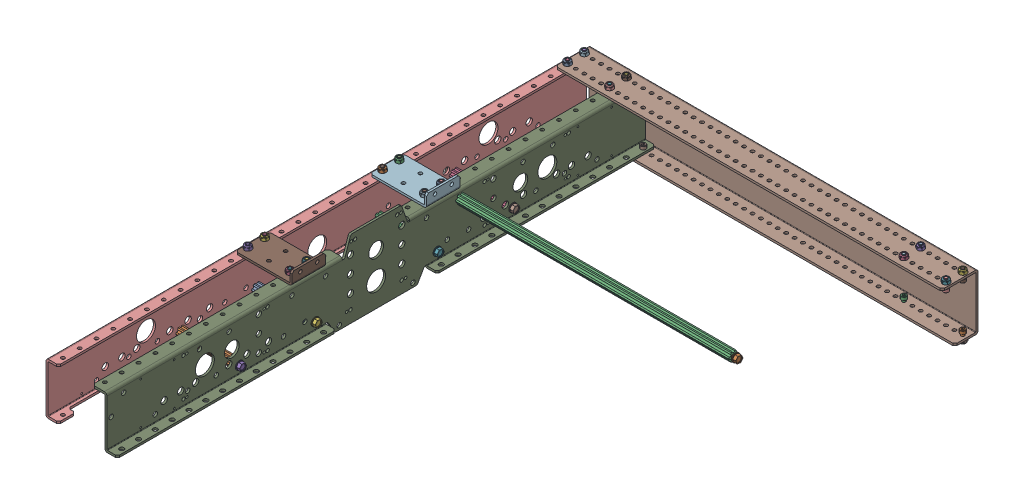
SolidWorks assembly AM14U3 Long Frame Half, configuration Default. Lengths in mm.
Overall size (596.14 116.33 816.74).
60 component instances, 9 part files, 0 mates.
Components (placement in the parent):
- Churro 3375-1: Churro 3375 [Default] at (-501.65 -66.929 448.437) x (0 0 1) z (-1 0 0) size (14.66 12.7 85.73)
- Churro 3375-2: Churro 3375 [Default] at (-501.65 -66.929 562.737) x (0 0 1) z (-1 0 0) size (14.66 12.7 85.73)
- Churro 3375-3: Churro 3375 [Default] at (-501.65 -66.929 264.287) x (0 0 1) z (-1 0 0) size (14.66 12.7 85.73)
- Churro 3375-4: Churro 3375 [Default] at (-501.65 -66.929 149.987) x (0 0 1) z (-1 0 0) size (14.66 12.7 85.73)
- FHTS 0.25-20-0.75_FHTS 0.25-20-G-0.75-C-1: FHTS 0.25-20-0.75_FHTS 0.25-20-G-0.75-C [Default] at (-498.475 -66.929 562.737) x (-1 0 0) z (0 0.924225 0.381849) size (24.64 12.19 12.19)
- FHTS 0.25-20-0.75_FHTS 0.25-20-G-0.75-C-2: FHTS 0.25-20-0.75_FHTS 0.25-20-G-0.75-C [Default] at (-498.475 -66.929 448.437) x (-1 0 0) z (0 0.924225 0.381849) size (24.64 12.19 12.19)
- FHTS 0.25-20-0.75_FHTS 0.25-20-G-0.75-C-3: FHTS 0.25-20-0.75_FHTS 0.25-20-G-0.75-C [Default] at (-498.475 -66.929 264.287) x (-1 0 0) z (0 0.924225 0.381849) size (24.64 12.19 12.19)
- FHTS 0.25-20-0.75_FHTS 0.25-20-G-0.75-C-4: FHTS 0.25-20-0.75_FHTS 0.25-20-G-0.75-C [Default] at (-498.475 -66.929 149.987) x (-1 0 0) z (0 0.924225 0.381849) size (24.64 12.19 12.19)
- FHTS 0.25-20-0.75_FHTS 0.25-20-G-0.75-C-5: FHTS 0.25-20-0.75_FHTS 0.25-20-G-0.75-C [Default] at (-590.55 -66.929 562.737) size (24.64 12.19 12.19)
- FHTS 0.25-20-0.75_FHTS 0.25-20-G-0.75-C-6: FHTS 0.25-20-0.75_FHTS 0.25-20-G-0.75-C [Default] at (-590.55 -66.929 448.437) size (24.64 12.19 12.19)
- FHTS 0.25-20-0.75_FHTS 0.25-20-G-0.75-C-7: FHTS 0.25-20-0.75_FHTS 0.25-20-G-0.75-C [Default] at (-590.55 -66.929 149.987) size (24.64 12.19 12.19)
- FHTS 0.25-20-0.75_FHTS 0.25-20-G-0.75-C-8: FHTS 0.25-20-0.75_FHTS 0.25-20-G-0.75-C [Default] at (-590.55 -66.929 264.287) size (24.64 12.19 12.19)
- FHTS 0.25-20-0.75_FHTS 0.25-20-G-0.75-C-9: FHTS 0.25-20-0.75_FHTS 0.25-20-G-0.75-C [Default] at (-501.65 -15.494 229.362) size (24.64 12.19 12.19)
- FHTS 0.25-20-0.75_FHTS 0.25-20-G-0.75-C-10: FHTS 0.25-20-0.75_FHTS 0.25-20-G-0.75-C [Default] at (-82.55 -15.494 229.362) x (-1 0 0) z (0 -0.924225 -0.381849) size (24.64 12.19 12.19)
- Churro 16250-1: Churro 16250 [Default] at (-85.725 -15.494 229.362) x (0 0 1) z (-1 0 0) size (14.66 12.7 412.75)
- 10-32x0500_shcs_HX-SHCS 0.19-32x1.375x1-C-1: 10-32x0500_shcs_HX-SHCS 0.19-32x1.375x1-C [Default] at (-577.85 -11.43 -11.938) x (0 1 0) z (0 0 1) size (17.53 7.94 7.94)
- 10-32x0500_shcs_HX-SHCS 0.19-32x1.375x1-C-2: 10-32x0500_shcs_HX-SHCS 0.19-32x1.375x1-C [Default] at (-577.85 -11.43 -37.338) x (0 1 0) z (0 0 1) size (17.53 7.94 7.94)
- 10-32x0500_shcs_HX-SHCS 0.19-32x1.375x1-C-3: 10-32x0500_shcs_HX-SHCS 0.19-32x1.375x1-C [Default] at (-514.35 -11.43 -37.338) x (0 1 0) z (0 0 1) size (17.53 7.94 7.94)
- 10-32x0500_shcs_HX-SHCS 0.19-32x1.375x1-C-4: 10-32x0500_shcs_HX-SHCS 0.19-32x1.375x1-C [Default] at (-514.35 -11.43 -11.938) x (0 1 0) z (0 0 1) size (17.53 7.94 7.94)
- 10-32x0500_shcs_HX-SHCS 0.19-32x1.375x1-C-5: 10-32x0500_shcs_HX-SHCS 0.19-32x1.375x1-C [Default] at (-488.95 -73.152 -37.338) x (0 -1 0) z (0 0 1) size (17.53 7.94 7.94)
- 10-32x0500_shcs_HX-SHCS 0.19-32x1.375x1-C-6: 10-32x0500_shcs_HX-SHCS 0.19-32x1.375x1-C [Default] at (-577.85 -73.152 -37.338) x (0 -1 0) z (0 0 1) size (17.53 7.94 7.94)
- 10-32x0500_shcs_HX-SHCS 0.19-32x1.375x1-C-7: 10-32x0500_shcs_HX-SHCS 0.19-32x1.375x1-C [Default] at (-6.35 -11.176 -11.938) x (0 1 0) z (-0.991845 0 0.127447) size (17.53 7.94 7.94)
- 10-32x0500_shcs_HX-SHCS 0.19-32x1.375x1-C-8: 10-32x0500_shcs_HX-SHCS 0.19-32x1.375x1-C [Default] at (-6.35 -11.176 -37.338) x (0 1 0) z (0.595464 0 0.803382) size (17.53 7.94 7.94)
- 10-32x0500_shcs_HX-SHCS 0.19-32x1.375x1-C-9: 10-32x0500_shcs_HX-SHCS 0.19-32x1.375x1-C [Default] at (-69.85 -11.176 -11.938) x (0 1 0) z (0.578861 0 0.815426) size (17.53 7.94 7.94)
- 10-32x0500_shcs_HX-SHCS 0.19-32x1.375x1-C-10: 10-32x0500_shcs_HX-SHCS 0.19-32x1.375x1-C [Default] at (-69.85 -11.176 -37.338) x (0 1 0) z (0.958905 0 0.283727) size (17.53 7.94 7.94)
- 10-32x0500_shcs_HX-SHCS 0.19-32x1.375x1-C-11: 10-32x0500_shcs_HX-SHCS 0.19-32x1.375x1-C [Default] at (-6.35 -73.406 -37.338) x (0 -1 0) z (-0.989362 0 -0.145473) size (17.53 7.94 7.94)
- 10-32x0500_shcs_HX-SHCS 0.19-32x1.375x1-C-12: 10-32x0500_shcs_HX-SHCS 0.19-32x1.375x1-C [Default] at (-95.25 -73.406 -37.338) x (0 -1 0) z (-0.875347 0 0.483496) size (17.53 7.94 7.94)
- 10-32 Nylock Nut-1: 10-32 Nylock Nut [Default] at (-69.85 0 -11.938) x (1 0 0) z (0 1 0) size (9.53 11 5.96)
- 10-32 Nylock Nut-2: 10-32 Nylock Nut [Default] at (-69.85 0 -37.338) x (1 0 0) z (0 1 0) size (9.53 11 5.96)
- 10-32 Nylock Nut-3: 10-32 Nylock Nut [Default] at (-6.35 0 -37.338) x (1 0 0) z (0 1 0) size (9.53 11 5.96)
- 10-32 Nylock Nut-4: 10-32 Nylock Nut [Default] at (-6.35 0 -11.938) x (1 0 0) z (0 1 0) size (9.53 11 5.96)
- 10-32 Nylock Nut-5: 10-32 Nylock Nut [Default] at (-6.35 -84.582 -37.338) x (1 0 0) z (0 -1 0) size (9.53 11 5.96)
- 10-32 Nylock Nut-6: 10-32 Nylock Nut [Default] at (-95.25 -84.582 -37.338) x (1 0 0) z (0 -1 0) size (9.53 11 5.96)
- 10-32 Nylock Nut-7: 10-32 Nylock Nut [Default] at (-514.35 0 -11.938) x (1 0 0) z (0 1 0) size (9.53 11 5.96)
- 10-32 Nylock Nut-8: 10-32 Nylock Nut [Default] at (-514.35 0 -37.338) x (1 0 0) z (0 1 0) size (9.53 11 5.96)
- 10-32 Nylock Nut-9: 10-32 Nylock Nut [Default] at (-577.85 0 -37.338) x (1 0 0) z (0 1 0) size (9.53 11 5.96)
- 10-32 Nylock Nut-10: 10-32 Nylock Nut [Default] at (-577.85 0 -11.938) x (1 0 0) z (0 1 0) size (9.53 11 5.96)
- 10-32 Nylock Nut-11: 10-32 Nylock Nut [Default] at (-488.95 -84.582 -37.338) x (1 0 0) z (0 -1 0) size (9.53 11 5.96)
- 10-32 Nylock Nut-12: 10-32 Nylock Nut [Default] at (-577.85 -84.582 -37.338) x (1 0 0) z (0 -1 0) size (9.53 11 5.96)
- 10-32x0500_shcs_HX-SHCS 0.19-32x1.375x1-C-13: 10-32x0500_shcs_HX-SHCS 0.19-32x1.375x1-C [Default] at (-577.85 -11.43 445.262) x (0 1 0) z (0 0 1) size (17.53 7.94 7.94)
- 10-32x0500_shcs_HX-SHCS 0.19-32x1.375x1-C-14: 10-32x0500_shcs_HX-SHCS 0.19-32x1.375x1-C [Default] at (-577.85 -11.43 470.662) x (0 1 0) z (0 0 1) size (17.53 7.94 7.94)
- 10-32x0500_shcs_HX-SHCS 0.19-32x1.375x1-C-15: 10-32x0500_shcs_HX-SHCS 0.19-32x1.375x1-C [Default] at (-514.35 -11.43 445.262) x (0 1 0) z (0 0 1) size (17.53 7.94 7.94)
- 10-32x0500_shcs_HX-SHCS 0.19-32x1.375x1-C-16: 10-32x0500_shcs_HX-SHCS 0.19-32x1.375x1-C [Default] at (-514.35 -11.43 470.662) x (0 1 0) z (0 0 1) size (17.53 7.94 7.94)
- 10-32x0500_shcs_HX-SHCS 0.19-32x1.375x1-C-17: 10-32x0500_shcs_HX-SHCS 0.19-32x1.375x1-C [Default] at (-577.85 -11.43 267.462) x (0 1 0) z (0 0 1) size (17.53 7.94 7.94)
- 10-32x0500_shcs_HX-SHCS 0.19-32x1.375x1-C-18: 10-32x0500_shcs_HX-SHCS 0.19-32x1.375x1-C [Default] at (-577.85 -11.43 242.062) x (0 1 0) z (0 0 1) size (17.53 7.94 7.94)
- 10-32x0500_shcs_HX-SHCS 0.19-32x1.375x1-C-19: 10-32x0500_shcs_HX-SHCS 0.19-32x1.375x1-C [Default] at (-514.35 -11.43 242.062) x (0 1 0) z (0 0 1) size (17.53 7.94 7.94)
- 10-32x0500_shcs_HX-SHCS 0.19-32x1.375x1-C-20: 10-32x0500_shcs_HX-SHCS 0.19-32x1.375x1-C [Default] at (-514.35 -11.43 267.462) x (0 1 0) z (0 0 1) size (17.53 7.94 7.94)
- 10-32 Nylock Nut-13: 10-32 Nylock Nut [Default] at (-514.35 -0.254 267.462) x (1 0 0) z (0 1 0) size (9.53 11 5.96)
- 10-32 Nylock Nut-14: 10-32 Nylock Nut [Default] at (-514.35 -0.254 242.062) x (1 0 0) z (0 1 0) size (9.53 11 5.96)
- 10-32 Nylock Nut-15: 10-32 Nylock Nut [Default] at (-577.85 -0.254 267.462) x (1 0 0) z (0 1 0) size (9.53 11 5.96)
- 10-32 Nylock Nut-16: 10-32 Nylock Nut [Default] at (-577.85 -0.254 242.062) x (1 0 0) z (0 1 0) size (9.53 11 5.96)
- 10-32 Nylock Nut-17: 10-32 Nylock Nut [Default] at (-514.35 -0.254 470.662) x (1 0 0) z (0 1 0) size (9.53 11 5.96)
- 10-32 Nylock Nut-18: 10-32 Nylock Nut [Default] at (-577.85 -0.254 470.662) x (1 0 0) z (0 1 0) size (9.53 11 5.96)
- 10-32 Nylock Nut-19: 10-32 Nylock Nut [Default] at (-577.85 -0.254 445.262) x (1 0 0) z (0 1 0) size (9.53 11 5.96)
- 10-32 Nylock Nut-20: 10-32 Nylock Nut [Default] at (-514.35 -0.254 445.262) x (1 0 0) z (0 1 0) size (9.53 11 5.96)
- AM14U3 End Sheet Long-1: AM14U3 End Sheet Long [Default] at (-488.098 60.9785 -76.8664) x (1 0 0) z (0 -1 0) size (584.2 53.97 84.58)
- AM14U3 Inside Sheet Rev2-1: AM14U3 Inside Sheet Rev2 [Default] at (-501.65 -77.216 762.762) x (0 0 -1) z (0 -1 0) size (812.8 38.1 116.33)
- AM14U3 Outside Sheet Rev1_DefaultSM-FLAT-PATTERN-1: AM14U3 Outside Sheet Rev1_DefaultSM-FLAT-PATTERN [Default] at (-587.375 -77.216 -50.038) x (0 0 1) z (0 -1 0) size (812.8 19.05 77.72)
- am-2954 AM14U2 2x3 Hole Bracket-1: am-2954 AM14U2 2x3 Hole Bracket [Default] at (-584.2 -3.429 496.062) size (85.73 19.05 50.8)
- am-2954 AM14U2 2x3 Hole Bracket-2: am-2954 AM14U2 2x3 Hole Bracket [Default] at (-584.2 -3.429 292.862) size (85.73 19.05 50.8)
